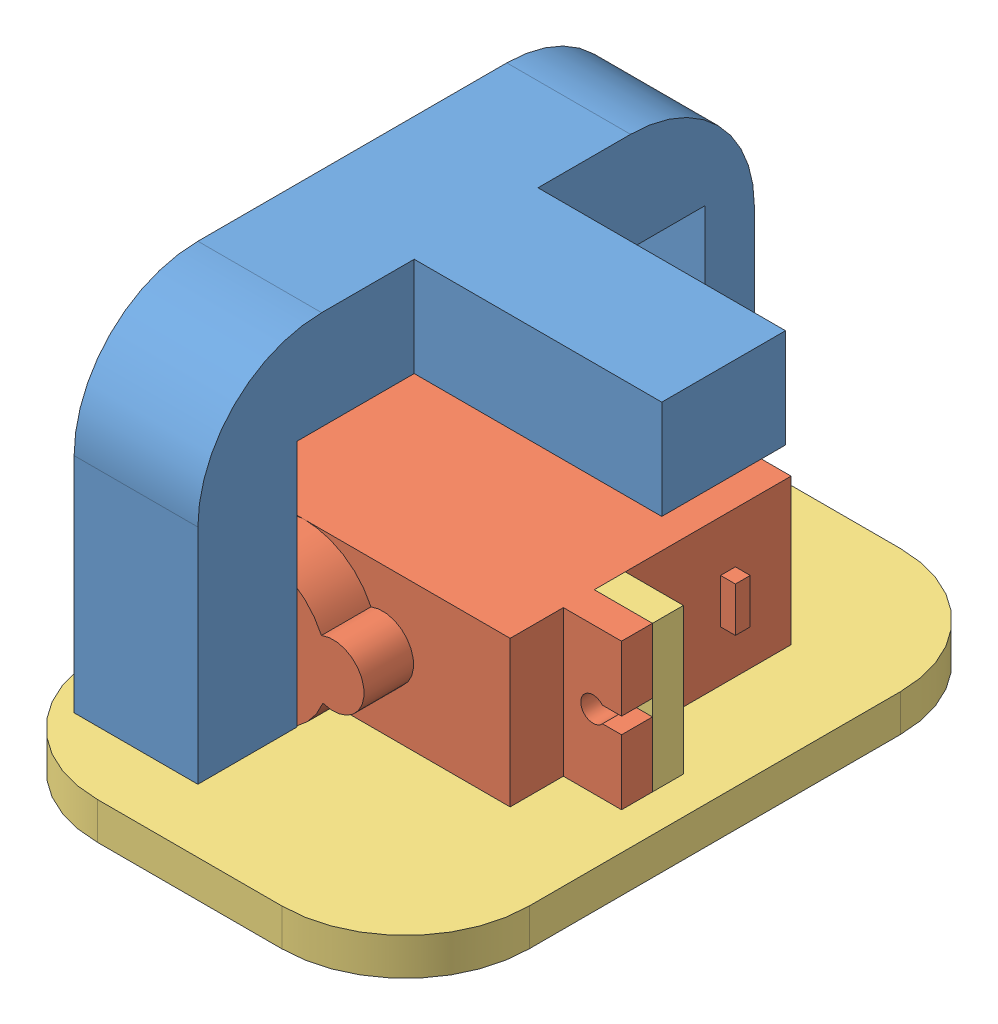
SolidWorks assembly assemblage pied, configuration Défaut. Lengths in mm.
Overall size (35.6 33.6 50).
3 component instances, 3 part files, 6 mates.
Components (placement in the parent):
- cheville-1: cheville [Défaut] at (-58.4675 6.0218 9.46) size (30 30 44.96)
- SG90_base-1: SG90_base [Défaut] at (-36.8675 15.2218 -18.87) x (1 0 0) z (0 -1 0) size (31.9 30.33 11.8)
- pied-1: pied [Défaut] at (-64.0675 0.4218 -30.02) size (34.9 14.8 50)
Mates (geometry in assembly coordinates):
- Parallèle1: parallel anti-aligned: plane of cheville-1 through (-58.4675 26.0218 -0.02) normal (0 -1 0); plane of SG90_base-1 through (-36.8675 15.2218 -18.87) normal (0 1 0)
- Distance2: distance = 1.63 mm: point of cheville-1; point of SG90_base-1
- Coaxiale1: concentric aligned: circle of cheville-1; circle of SG90_base-1
- Coïncidente1: coincident anti-aligned: plane of SG90_base-1 through (-36.8675 3.4218 -18.87) normal (0 -1 0); plane of pied-1 through (-64.0675 3.4218 19.98) normal (0 1 0)
- Coïncidente3: coincident anti-aligned: line of pied-1 through (-32.1675 3.4218 -5.02) axis (-1 0 0); line of assembly
- Coïncidente6: coincident aligned: plane of SG90_base-1 through (-64.0675 3.4218 -2.97) normal (-1 0 0); plane of pied-1 through (-64.0675 0.4218 19.98) normal (-1 0 0)
